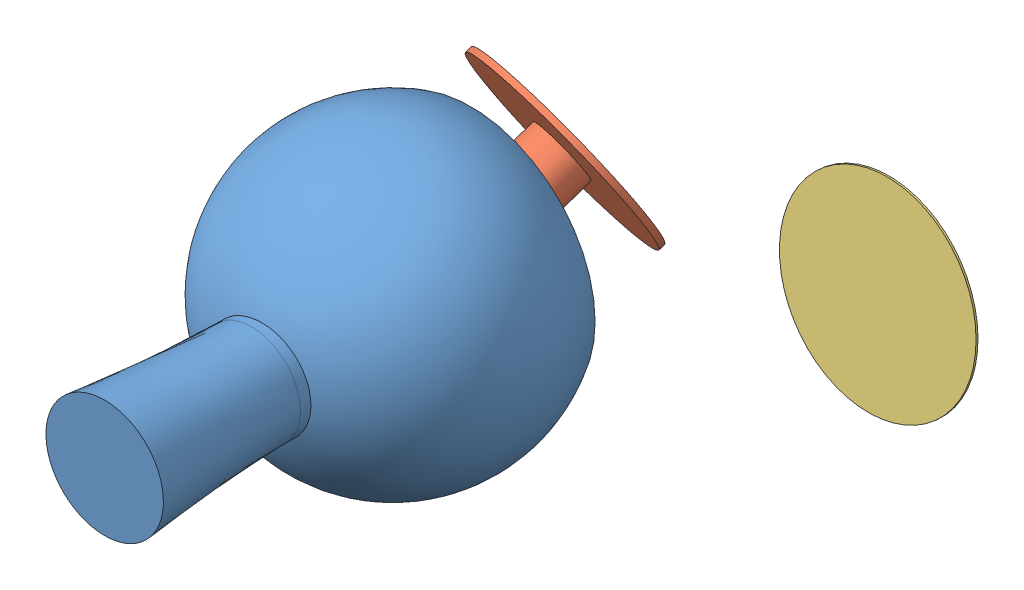
SolidWorks assembly Bras 1 (émanté), configuration Default. Lengths in mm.
Overall size (505.12 371.61 574.55).
3 component instances, 3 part files, 1 mates.
Components (placement in the parent):
- bras-1: bras [Default] at (8.6242 187.6077 180.0952) size (300 300 380)
- partie émant-1: partie émant [Default] at (35.8291 190.9455 156.9603) x (0.982361 -0.026702 0.185079) z (0.171663 0.521272 -0.835947) size (250 250 291)
- émant collé sur le telephone-1: émant collé sur le telephone [Default] at (392.9763 174.3624 -83.2218) x (0.981627 -0.189931 0.018288) z (0 0.095846 0.995396) size (200 200 2)
Mates (geometry in assembly coordinates):
- Concentric2: concentric: sphere of bras-1; sphere of partie émant-1
